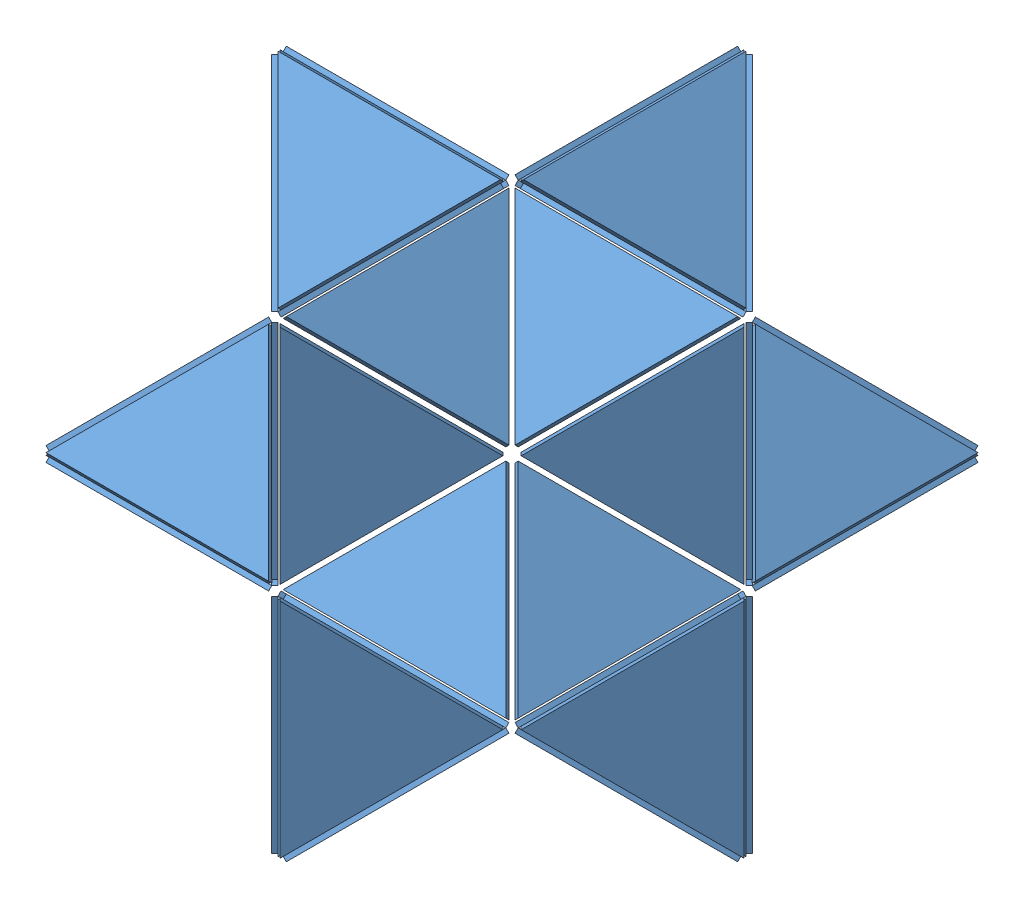
SolidWorks assembly Rhombic Dodecahedron Pyramid Plates, configuration Default. Lengths in mm.
Overall size (318.55 318.55 318.55).
65 component instances, 2 part files, 4 mates.
Components (placement in the parent):
- PFRD-1: PFRD [Default] at origin size (320.02 320.02 320.02) (hidden)
- Part1^Rhombic Dodecahedron Pyramid Plates-116: Part1^Rhombic Dodecahedron Pyramid Plates [Default] at (0 80.005 80.005) x (1 0 0) z (0 0.707107 0.707107) size (150.2 106.2 3) (hidden, virtual)
- Part1^Rhombic Dodecahedron Pyramid Plates-117: Part1^Rhombic Dodecahedron Pyramid Plates [Default] at (0 80.005 -80.005) x (1 0 0) z (0 -0.707107 0.707107) size (150.2 106.2 3) (hidden, virtual)
- Part1^Rhombic Dodecahedron Pyramid Plates-118: Part1^Rhombic Dodecahedron Pyramid Plates [Default] at (80.005 0 80.005) x (0 1 0) z (-0.707107 0 -0.707107) size (150.2 106.2 3) (hidden, virtual)
- Part1^Rhombic Dodecahedron Pyramid Plates-119: Part1^Rhombic Dodecahedron Pyramid Plates [Default] at (80.005 0 -80.005) x (0 1 0) z (0.707107 0 -0.707107) size (150.2 106.2 3) (hidden, virtual)
- Part1^Rhombic Dodecahedron Pyramid Plates-120: Part1^Rhombic Dodecahedron Pyramid Plates [Default] at (-80.005 0 80.005) x (0 1 0) z (0.707107 0 -0.707107) size (150.2 106.2 3) (virtual)
- Part1^Rhombic Dodecahedron Pyramid Plates-121: Part1^Rhombic Dodecahedron Pyramid Plates [Default] at (-80.005 0 -80.005) x (0 1 0) z (0.707107 0 0.707107) size (150.2 106.2 3) (virtual)
- Part1^Rhombic Dodecahedron Pyramid Plates-122: Part1^Rhombic Dodecahedron Pyramid Plates [Default] at (80.005 0 80.005) x (0 1 0) z (0.707107 0 0.707107) size (150.2 106.2 3) (virtual)
- Part1^Rhombic Dodecahedron Pyramid Plates-123: Part1^Rhombic Dodecahedron Pyramid Plates [Default] at (-80.005 0 80.005) x (0 1 0) z (-0.707107 0 0.707107) size (150.2 106.2 3) (virtual)
- Part1^Rhombic Dodecahedron Pyramid Plates-124: Part1^Rhombic Dodecahedron Pyramid Plates [Default] at (80.005 80.005 0) x (0 0 1) z (-0.707107 -0.707107 0) size (150.2 106.2 3) (virtual)
- Part1^Rhombic Dodecahedron Pyramid Plates-125: Part1^Rhombic Dodecahedron Pyramid Plates [Default] at (0 80.005 80.005) x (-1 0 0) z (0 -0.707107 -0.707107) size (150.2 106.2 3) (virtual)
- Part1^Rhombic Dodecahedron Pyramid Plates-126: Part1^Rhombic Dodecahedron Pyramid Plates [Default] at (-80.005 80.005 0) x (0 0 1) z (-0.707107 0.707107 0) size (150.2 106.2 3) (virtual)
- Part1^Rhombic Dodecahedron Pyramid Plates-127: Part1^Rhombic Dodecahedron Pyramid Plates [Default] at (0 80.005 -80.005) x (-1 0 0) z (0 0.707107 -0.707107) size (150.2 106.2 3) (virtual)
- Part1^Rhombic Dodecahedron Pyramid Plates-128: Part1^Rhombic Dodecahedron Pyramid Plates [Default] at (80.005 0 -80.005) x (0 1 0) z (-0.707107 0 0.707107) size (150.2 106.2 3) (virtual)
- Part1^Rhombic Dodecahedron Pyramid Plates-129: Part1^Rhombic Dodecahedron Pyramid Plates [Default] at (-80.005 0 -80.005) x (0 1 0) z (-0.707107 0 -0.707107) size (150.2 106.2 3) (virtual)
- Part1^Rhombic Dodecahedron Pyramid Plates-130: Part1^Rhombic Dodecahedron Pyramid Plates [Default] at (-80.005 80.005 0) x (0 0 -1) z (0.707107 -0.707107 0) size (150.2 106.2 3) (virtual)
- Part1^Rhombic Dodecahedron Pyramid Plates-131: Part1^Rhombic Dodecahedron Pyramid Plates [Default] at (80.005 80.005 0) x (0 0 -1) z (0.707107 0.707107 0) size (150.2 106.2 3) (virtual)
- Part1^Rhombic Dodecahedron Pyramid Plates-132: Part1^Rhombic Dodecahedron Pyramid Plates [Default] at (-80.005 0 80.005) x (0 1 0) z (-0.707107 0 0.707107) size (150.2 106.2 3) (virtual)
- Part1^Rhombic Dodecahedron Pyramid Plates-133: Part1^Rhombic Dodecahedron Pyramid Plates [Default] at (0 -80.005 80.005) x (-1 0 0) z (0 -0.707107 0.707107) size (150.2 106.2 3) (virtual)
- Part1^Rhombic Dodecahedron Pyramid Plates-134: Part1^Rhombic Dodecahedron Pyramid Plates [Default] at (80.005 0 80.005) x (0 -1 0) z (0.707107 0 0.707107) size (150.2 106.2 3) (virtual)
- Part1^Rhombic Dodecahedron Pyramid Plates-135: Part1^Rhombic Dodecahedron Pyramid Plates [Default] at (-80.005 0 -80.005) x (0 1 0) z (0.707107 0 0.707107) size (150.2 106.2 3) (virtual)
- Part1^Rhombic Dodecahedron Pyramid Plates-136: Part1^Rhombic Dodecahedron Pyramid Plates [Default] at (0 -80.005 -80.005) x (-1 0 0) z (0 0.707107 0.707107) size (150.2 106.2 3) (virtual)
- Part1^Rhombic Dodecahedron Pyramid Plates-137: Part1^Rhombic Dodecahedron Pyramid Plates [Default] at (80.005 0 -80.005) x (0 -1 0) z (-0.707107 0 0.707107) size (150.2 106.2 3) (virtual)
- Part1^Rhombic Dodecahedron Pyramid Plates-138: Part1^Rhombic Dodecahedron Pyramid Plates [Default] at (0 80.005 80.005) x (-1 0 0) z (0 -0.707107 -0.707107) size (150.2 106.2 3) (virtual)
- Part1^Rhombic Dodecahedron Pyramid Plates-139: Part1^Rhombic Dodecahedron Pyramid Plates [Default] at (-80.005 0 80.005) x (0 -1 0) z (0.707107 0 -0.707107) size (150.2 106.2 3) (virtual)
- Part1^Rhombic Dodecahedron Pyramid Plates-140: Part1^Rhombic Dodecahedron Pyramid Plates [Default] at (0 -80.005 80.005) x (1 0 0) z (0 0.707107 -0.707107) size (150.2 106.2 3) (virtual)
- Part1^Rhombic Dodecahedron Pyramid Plates-141: Part1^Rhombic Dodecahedron Pyramid Plates [Default] at (0 80.005 -80.005) x (-1 0 0) z (0 0.707107 -0.707107) size (150.2 106.2 3) (virtual)
- Part1^Rhombic Dodecahedron Pyramid Plates-142: Part1^Rhombic Dodecahedron Pyramid Plates [Default] at (-80.005 0 -80.005) x (0 -1 0) z (-0.707107 0 -0.707107) size (150.2 106.2 3) (virtual)
- Part1^Rhombic Dodecahedron Pyramid Plates-143: Part1^Rhombic Dodecahedron Pyramid Plates [Default] at (0 -80.005 -80.005) x (1 0 0) z (0 -0.707107 -0.707107) size (150.2 106.2 3) (virtual)
- Part1^Rhombic Dodecahedron Pyramid Plates-144: Part1^Rhombic Dodecahedron Pyramid Plates [Default] at (0 -80.005 80.005) x (-1 0 0) z (0 0.707107 -0.707107) size (150.2 106.2 3) (virtual)
- Part1^Rhombic Dodecahedron Pyramid Plates-145: Part1^Rhombic Dodecahedron Pyramid Plates [Default] at (80.005 0 80.005) x (0 -1 0) z (-0.707107 0 -0.707107) size (150.2 106.2 3) (virtual)
- Part1^Rhombic Dodecahedron Pyramid Plates-146: Part1^Rhombic Dodecahedron Pyramid Plates [Default] at (0 80.005 80.005) x (1 0 0) z (0 -0.707107 -0.707107) size (150.2 106.2 3) (virtual)
- Part1^Rhombic Dodecahedron Pyramid Plates-147: Part1^Rhombic Dodecahedron Pyramid Plates [Default] at (0 -80.005 -80.005) x (-1 0 0) z (0 0.707107 0.707107) size (150.2 106.2 3) (virtual)
- Part1^Rhombic Dodecahedron Pyramid Plates-148: Part1^Rhombic Dodecahedron Pyramid Plates [Default] at (80.005 0 -80.005) x (0 -1 0) z (-0.707107 0 0.707107) size (150.2 106.2 3) (virtual)
- Part1^Rhombic Dodecahedron Pyramid Plates-149: Part1^Rhombic Dodecahedron Pyramid Plates [Default] at (0 80.005 -80.005) x (1 0 0) z (0 -0.707107 0.707107) size (150.2 106.2 3) (virtual)
- Part1^Rhombic Dodecahedron Pyramid Plates-150: Part1^Rhombic Dodecahedron Pyramid Plates [Default] at (0 80.005 80.005) x (-1 0 0) z (0 0.707107 0.707107) size (150.2 106.2 3) (virtual)
- Part1^Rhombic Dodecahedron Pyramid Plates-151: Part1^Rhombic Dodecahedron Pyramid Plates [Default] at (-80.005 0 80.005) x (0 -1 0) z (-0.707107 0 0.707107) size (150.2 106.2 3) (virtual)
- Part1^Rhombic Dodecahedron Pyramid Plates-152: Part1^Rhombic Dodecahedron Pyramid Plates [Default] at (0 -80.005 80.005) x (1 0 0) z (0 -0.707107 0.707107) size (150.2 106.2 3) (virtual)
- Part1^Rhombic Dodecahedron Pyramid Plates-153: Part1^Rhombic Dodecahedron Pyramid Plates [Default] at (0 -80.005 80.005) x (-1 0 0) z (0 -0.707107 0.707107) size (150.2 106.2 3) (virtual)
- Part1^Rhombic Dodecahedron Pyramid Plates-154: Part1^Rhombic Dodecahedron Pyramid Plates [Default] at (80.005 0 80.005) x (0 -1 0) z (0.707107 0 0.707107) size (150.2 106.2 3) (virtual)
- Part1^Rhombic Dodecahedron Pyramid Plates-155: Part1^Rhombic Dodecahedron Pyramid Plates [Default] at (0 80.005 80.005) x (1 0 0) z (0 0.707107 0.707107) size (150.2 106.2 3) (virtual)
- Part1^Rhombic Dodecahedron Pyramid Plates-156: Part1^Rhombic Dodecahedron Pyramid Plates [Default] at (-80.005 80.005 0) x (0 0 1) z (0.707107 -0.707107 0) size (150.2 106.2 3) (virtual)
- Part1^Rhombic Dodecahedron Pyramid Plates-157: Part1^Rhombic Dodecahedron Pyramid Plates [Default] at (-80.005 -80.005 0) x (0 0 1) z (0.707107 0.707107 0) size (150.2 106.2 3) (virtual)
- Part1^Rhombic Dodecahedron Pyramid Plates-158: Part1^Rhombic Dodecahedron Pyramid Plates [Default] at (80.005 -80.005 0) x (0 0 1) z (-0.707107 0.707107 0) size (150.2 106.2 3) (virtual)
- Part1^Rhombic Dodecahedron Pyramid Plates-159: Part1^Rhombic Dodecahedron Pyramid Plates [Default] at (-80.005 0 80.005) x (0 -1 0) z (0.707107 0 -0.707107) size (150.2 106.2 3) (virtual)
- Part1^Rhombic Dodecahedron Pyramid Plates-160: Part1^Rhombic Dodecahedron Pyramid Plates [Default] at (0 -80.005 80.005) x (1 0 0) z (0 0.707107 -0.707107) size (150.2 106.2 3) (virtual)
- Part1^Rhombic Dodecahedron Pyramid Plates-161: Part1^Rhombic Dodecahedron Pyramid Plates [Default] at (80.005 0 80.005) x (0 1 0) z (-0.707107 0 -0.707107) size (150.2 106.2 3) (virtual)
- Part1^Rhombic Dodecahedron Pyramid Plates-162: Part1^Rhombic Dodecahedron Pyramid Plates [Default] at (-80.005 -80.005 0) x (0 0 1) z (-0.707107 -0.707107 0) size (150.2 106.2 3) (virtual)
- Part1^Rhombic Dodecahedron Pyramid Plates-163: Part1^Rhombic Dodecahedron Pyramid Plates [Default] at (80.005 -80.005 0) x (0 0 1) z (0.707107 -0.707107 0) size (150.2 106.2 3) (virtual)
- Part1^Rhombic Dodecahedron Pyramid Plates-164: Part1^Rhombic Dodecahedron Pyramid Plates [Default] at (80.005 80.005 0) x (0 0 1) z (0.707107 0.707107 0) size (150.2 106.2 3) (virtual)
- Part1^Rhombic Dodecahedron Pyramid Plates-165: Part1^Rhombic Dodecahedron Pyramid Plates [Default] at (-80.005 0 -80.005) x (0 -1 0) z (-0.707107 0 -0.707107) size (150.2 106.2 3) (virtual)
- Part1^Rhombic Dodecahedron Pyramid Plates-166: Part1^Rhombic Dodecahedron Pyramid Plates [Default] at (0 -80.005 -80.005) x (1 0 0) z (0 -0.707107 -0.707107) size (150.2 106.2 3) (virtual)
- Part1^Rhombic Dodecahedron Pyramid Plates-167: Part1^Rhombic Dodecahedron Pyramid Plates [Default] at (80.005 0 -80.005) x (0 1 0) z (0.707107 0 -0.707107) size (150.2 106.2 3) (virtual)
- Part1^Rhombic Dodecahedron Pyramid Plates-168: Part1^Rhombic Dodecahedron Pyramid Plates [Default] at (0 80.005 -80.005) x (-1 0 0) z (0 -0.707107 0.707107) size (150.2 106.2 3) (virtual)
- Part1^Rhombic Dodecahedron Pyramid Plates-169: Part1^Rhombic Dodecahedron Pyramid Plates [Default] at (-80.005 0 -80.005) x (0 -1 0) z (0.707107 0 0.707107) size (150.2 106.2 3) (virtual)
- Part1^Rhombic Dodecahedron Pyramid Plates-170: Part1^Rhombic Dodecahedron Pyramid Plates [Default] at (0 -80.005 -80.005) x (1 0 0) z (0 0.707107 0.707107) size (150.2 106.2 3) (virtual)
- Part1^Rhombic Dodecahedron Pyramid Plates-171: Part1^Rhombic Dodecahedron Pyramid Plates [Default] at (0 -80.005 -80.005) x (-1 0 0) z (0 -0.707107 -0.707107) size (150.2 106.2 3) (virtual)
- Part1^Rhombic Dodecahedron Pyramid Plates-172: Part1^Rhombic Dodecahedron Pyramid Plates [Default] at (80.005 0 -80.005) x (0 -1 0) z (0.707107 0 -0.707107) size (150.2 106.2 3) (virtual)
- Part1^Rhombic Dodecahedron Pyramid Plates-173: Part1^Rhombic Dodecahedron Pyramid Plates [Default] at (0 80.005 -80.005) x (1 0 0) z (0 0.707107 -0.707107) size (150.2 106.2 3) (virtual)
- Part1^Rhombic Dodecahedron Pyramid Plates-174: Part1^Rhombic Dodecahedron Pyramid Plates [Default] at (-80.005 -80.005 0) x (0 0 -1) z (0.707107 0.707107 0) size (150.2 106.2 3) (virtual)
- Part1^Rhombic Dodecahedron Pyramid Plates-175: Part1^Rhombic Dodecahedron Pyramid Plates [Default] at (80.005 -80.005 0) x (0 0 -1) z (-0.707107 0.707107 0) size (150.2 106.2 3) (virtual)
- Part1^Rhombic Dodecahedron Pyramid Plates-176: Part1^Rhombic Dodecahedron Pyramid Plates [Default] at (80.005 80.005 0) x (0 0 -1) z (-0.707107 -0.707107 0) size (150.2 106.2 3) (virtual)
- Part1^Rhombic Dodecahedron Pyramid Plates-177: Part1^Rhombic Dodecahedron Pyramid Plates [Default] at (-80.005 80.005 0) x (0 0 -1) z (-0.707107 0.707107 0) size (150.2 106.2 3) (virtual)
- Part1^Rhombic Dodecahedron Pyramid Plates-178: Part1^Rhombic Dodecahedron Pyramid Plates [Default] at (-80.005 -80.005 0) x (0 0 -1) z (-0.707107 -0.707107 0) size (150.2 106.2 3) (virtual)
- Part1^Rhombic Dodecahedron Pyramid Plates-179: Part1^Rhombic Dodecahedron Pyramid Plates [Default] at (80.005 -80.005 0) x (0 0 -1) z (0.707107 -0.707107 0) size (150.2 106.2 3) (virtual)
Mates (geometry in assembly coordinates):
- InPlace1: in place: plane of PFRD-1 through (160.01 160.01 0) normal (0 0.707107 0.707107); plane of ? through (0 80.005 80.005) normal (0 0.707107 0.707107); moOrthogonalPlaneRef_w of PFRD-1 through (160.01 160.01 0) normal (0 0.707107 0.707107); plane of ? through (0 80.005 80.005) normal (0 0.707107 -0.707107); plane of PFRD-1 through (160.01 160.01 0) normal (0 0.707107 0.707107); plane of ? through (0 80.005 80.005) normal (1 0 0); plane of PFRD-1 through (160.01 160.01 0) normal (0 0.707107 0.707107); unknown of ?
- Coincident1: coincident aligned: plane of PFRD-1; plane of Part1^Rhombic Dodecahedron Pyramid Plates-116
- Coincident2: coincident aligned: moOrthogonalPlaneRef_w of PFRD-1 through (0 80.005 80.005) normal (0 0.707107 -0.707107); plane of Part1^Rhombic Dodecahedron Pyramid Plates-116 through (0 80.005 80.005) normal (0 0.707107 -0.707107)
- Coincident3: coincident anti-aligned: moOrthogonalPlaneRef_w of PFRD-1 through (0 80.005 80.005) normal (-1 0 0); plane of Part1^Rhombic Dodecahedron Pyramid Plates-116 through (0 80.005 80.005) normal (1 0 0)
